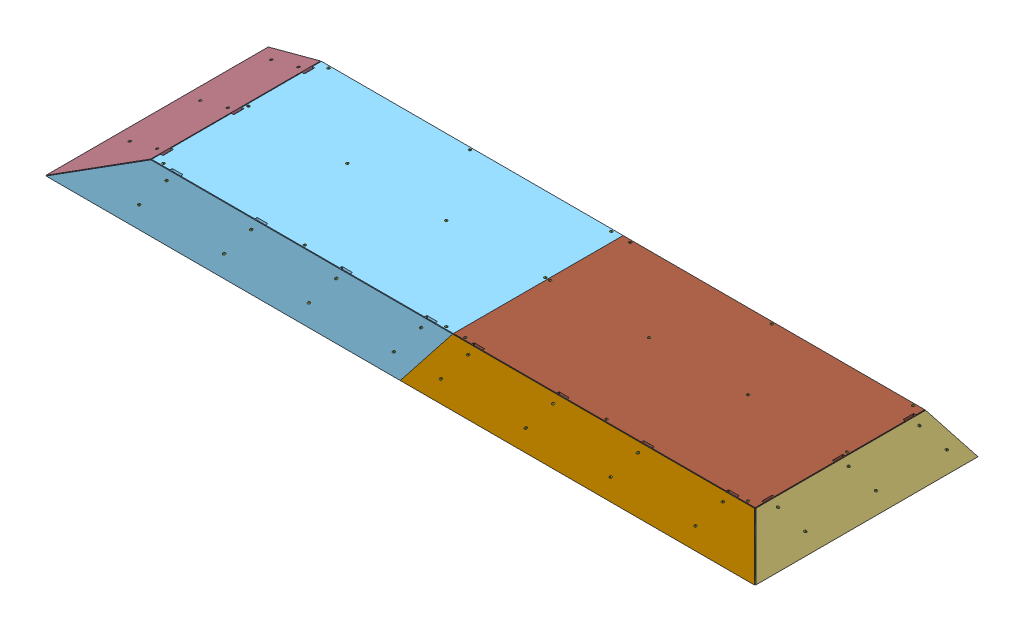
SolidWorks assembly GE-19062, configuration Default. Lengths in mm.
Overall size (3824.12 126.58 1202.44).
172 component instances, 14 part files, 19 mates.
Components (placement in the parent):
- GE-19067-1: GE-19067 [GE-19067-red] at (605.9548 862.858 1212.4726) size (1625.6 77.99 917.59)
  - GE-19063-1: GE-19063 [Default] at origin size (1625.6 63.5 917.59)
    - GE-19066-2: GE-19066 [Default] at (812.8 0 -457.2) x (0 0 -1) z (1 0 0) size (25.4 63.5 1625.6)
    - GE-19064-2: GE-19064 [Default] at (-812.8 0 -430.5376) x (-1 0 0) z (0 0 -1) size (25.4 63.5 910.59)
    - GE-19064-3: GE-19064 [Default] at (812.8 0 430.5224) size (25.4 63.5 910.59)
    - GE-19066-3: GE-19066 [Default] at (-812.8 0 457.1848) x (0 0 1) z (-1 0 0) size (25.4 63.5 1625.6)
    - GE-19065-1: GE-19065 [Default] at (279.4 0 -0.0076) size (25.4 63.5 910.59)
    - GE-19065-2: GE-19065 [Default] at (-279.4 63.5 -0.0076) x (-1 0 0) z (0 0 1) size (25.4 63.5 910.59)
    - rivet_.1875_.126-.25-2: rivet_.1875_.126-.25 [Default] at (-800.1 50.8 457.1848) size (10.01 10.01 13.03)
    - rivet_.1875_.126-.25-10: rivet_.1875_.126-.25 [Default] at (-266.7 50.8 457.1848) x (0.959125 0.282984 0) z (0 0 1) size (10.01 10.01 13.03)
    - rivet_.1875_.126-.25-11: rivet_.1875_.126-.25 [Default] at (-266.7 12.7 457.1848) x (0.928571 0.371154 0) z (0 0 1) size (10.01 10.01 13.03)
    - rivet_.1875_.126-.25-12: rivet_.1875_.126-.25 [Default] at (266.7 50.8 457.1848) x (0.906989 0.421154 0) z (0 0 1) size (10.01 10.01 13.03)
    - rivet_.1875_.126-.25-13: rivet_.1875_.126-.25 [Default] at (266.7 12.7 457.1848) x (0.902849 0.429957 0) z (0 0 1) size (10.01 10.01 13.03)
    - rivet_.1875_.126-.25-14: rivet_.1875_.126-.25 [Default] at (800.1 50.8 457.1848) x (0.919615 0.39282 0) z (0 0 1) size (10.01 10.01 13.03)
    - rivet_.1875_.126-.25-15: rivet_.1875_.126-.25 [Default] at (800.1 12.7 457.1848) x (0.952324 0.305088 0) z (0 0 1) size (10.01 10.01 13.03)
    - rivet_.1875_.126-.25-18: rivet_.1875_.126-.25 [Default] at (-800.1 12.7 457.1848) x (0.987351 0.158553 0) z (0 0 1) size (10.01 10.01 13.03)
    - rivet_.1875_.126-.25-20: rivet_.1875_.126-.25 [Default] at (800.1 50.8 -457.2) x (1 0 0) z (0 0 -1) size (10.01 10.01 13.03)
    - rivet_.1875_.126-.25-21: rivet_.1875_.126-.25 [Default] at (800.1 12.7 -457.2) x (0.987351 0.158553 0) z (0 0 -1) size (10.01 10.01 13.03)
    - rivet_.1875_.126-.25-22: rivet_.1875_.126-.25 [Default] at (266.7 50.8 -457.2) x (0.959125 0.282984 0) z (0 0 -1) size (10.01 10.01 13.03)
    - rivet_.1875_.126-.25-23: rivet_.1875_.126-.25 [Default] at (266.7 12.7 -457.2) x (0.928571 0.371154 0) z (0 0 -1) size (10.01 10.01 13.03)
    - rivet_.1875_.126-.25-24: rivet_.1875_.126-.25 [Default] at (-266.7 50.8 -457.2) x (0.906989 0.421154 0) z (0 0 -1) size (10.01 10.01 13.03)
    - rivet_.1875_.126-.25-25: rivet_.1875_.126-.25 [Default] at (-266.7 12.7 -457.2) x (0.902849 0.429957 0) z (0 0 -1) size (10.01 10.01 13.03)
    - rivet_.1875_.126-.25-26: rivet_.1875_.126-.25 [Default] at (-800.1 50.8 -457.2) x (0.919615 0.39282 0) z (0 0 -1) size (10.01 10.01 13.03)
    - rivet_.1875_.126-.25-27: rivet_.1875_.126-.25 [Default] at (-800.1 12.7 -457.2) x (0.952324 0.305088 0) z (0 0 -1) size (10.01 10.01 13.03)
  - GE-19068-1: GE-19068 [GE-19068-red] at (812.8 76.2 457.1848) x (-1 0 0) z (0 0 1) size (1625.6 12.7 914.4)
  - nylock_.25_20-1: nylock_.25_20 [Default] at (-762 61.6026 444.4848) x (-1 0 0) z (0 0 1) size (11.11 7.94 12.83)
  - nylock_.25_20-2: nylock_.25_20 [Default] at (0 61.6026 444.4848) x (-0.982082 0 0.188455) z (0.188455 0 0.982082) size (11.11 7.94 12.83)
  - nylock_.25_20-3: nylock_.25_20 [Default] at (762 61.6026 444.4848) x (-0.918365 0 0.395734) z (0.395734 0 0.918365) size (11.11 7.94 12.83)
  - nylock_.25_20-4: nylock_.25_20 [Default] at (800.1 61.6026 -50.8076) x (-0.8 0 0.6) z (0.6 0 0.8) size (11.11 7.94 12.83)
  - nylock_.25_20-5: nylock_.25_20 [Default] at (266.7 61.6026 -50.8076) x (-0.63358 0 0.773678) z (0.773678 0 0.63358) size (11.11 7.94 12.83)
  - nylock_.25_20-8: nylock_.25_20 [Default] at (-800.1 61.6026 -50.8076) x (0.999877 0 -0.015704) z (-0.015704 0 -0.999877) size (11.11 7.94 12.83)
  - nylock_.25_20-9: nylock_.25_20 [Default] at (-762 61.6026 -444.5) x (-0.263225 0 0.964735) z (0.964735 0 0.263225) size (11.11 7.94 12.83)
  - nylock_.25_20-10: nylock_.25_20 [Default] at (0 61.6026 -444.5) x (-0.120178 0 0.992752) z (0.992752 0 0.120178) size (11.11 7.94 12.83)
  - nylock_.25_20-11: nylock_.25_20 [Default] at (762 61.6026 -444.5) x (-0.030377 0 0.999538) z (0.999538 0 0.030377) size (11.11 7.94 12.83)
  - nylock_.25_20-12: nylock_.25_20 [Default] at (-266.7 61.6026 -50.8076) x (0.546944 0 0.837169) z (0.837169 0 -0.546944) size (11.11 7.94 12.83)
  - flat_hex_.25_20_1-1: flat_hex_.25_20_1 [91253A542] at (762 76.2 -444.5152) x (1 0 0) z (0 1 0) size (13.49 13.49 25.61)
  - flat_hex_.25_20_1-12: flat_hex_.25_20_1 [91253A542] at (0 76.2 -444.5152) x (0.982082 0 -0.188455) z (0 1 0) size (13.49 13.49 25.61)
  - flat_hex_.25_20_1-13: flat_hex_.25_20_1 [91253A542] at (-762 76.2 -444.5152) x (0.918365 0 -0.395734) z (0 1 0) size (13.49 13.49 25.61)
  - flat_hex_.25_20_1-14: flat_hex_.25_20_1 [91253A542] at (-800.1 76.2 -50.8152) x (0.8 0 -0.6) z (0 1 0) size (13.49 13.49 25.61)
  - flat_hex_.25_20_1-15: flat_hex_.25_20_1 [91253A542] at (-762 76.2 444.4848) x (0.63358 0 -0.773678) z (0 1 0) size (13.49 13.49 25.61)
  - flat_hex_.25_20_1-16: flat_hex_.25_20_1 [91253A542] at (0 76.2 444.4848) x (0.443629 0 -0.896211) z (0 1 0) size (13.49 13.49 25.61)
  - flat_hex_.25_20_1-17: flat_hex_.25_20_1 [91253A542] at (-266.7 76.2 -50.8152) x (0.263225 0 -0.964735) z (0 1 0) size (13.49 13.49 25.61)
  - flat_hex_.25_20_1-18: flat_hex_.25_20_1 [91253A542] at (266.7 76.2 -50.8152) x (0.120178 0 -0.992752) z (0 1 0) size (13.49 13.49 25.61)
  - flat_hex_.25_20_1-19: flat_hex_.25_20_1 [91253A542] at (762 76.2 444.4848) x (0.030377 0 -0.999538) z (0 1 0) size (13.49 13.49 25.61)
  - flat_hex_.25_20_1-20: flat_hex_.25_20_1 [91253A542] at (800.1 76.2 -50.8152) x (0 0 -1) z (0 1 0) size (13.49 13.49 25.61)
  - Hook_1_36-1: Hook_1_36 [Default] at (-787.4 -1.5875 457.2) x (0 0 -1) z (1 0 0) size (914.4 1.59 25.4)
  - Hook_1_36-2: Hook_1_36 [Default] at (812.8 -1.5875 457.2) x (0 0 -1) z (1 0 0) size (914.4 1.59 25.4)
- GE-19053-1: GE-19053 [Default] at (2243.466 893.8913 1808.0826) x (1 0 0) z (0 -0.259056 0.965862) size (1908.66 51.01 298.45)
  - GE-19054-1: GE-19054 [Default] at (-11.9112 -4.3385 -141.1312) size (1908.66 12.7 292.1)
  - GE-19055-1: GE-19055 [Default] at (-719.9362 -42.4385 -142.706) size (44.45 38.1 228.6)
  - GE-19055-2: GE-19055 [Default] at (-262.7362 -42.4385 -142.706) size (44.45 38.1 228.6)
  - GE-19055-3: GE-19055 [Default] at (194.4638 -42.4385 -142.706) size (44.45 38.1 228.6)
  - GE-19055-4: GE-19055 [Default] at (651.6638 -42.4385 -142.706) size (44.45 38.1 228.6)
  - nylock_.25_20-1: nylock_.25_20 [Default] at (673.8888 -9.1137 -96.6812) x (-1 0 0) z (0 0 1) size (11.11 7.94 12.83)
  - nylock_.25_20-2: nylock_.25_20 [Default] at (673.8888 -9.1137 55.7188) x (-0.982082 0 0.188455) z (0.188455 0 0.982082) size (11.11 7.94 12.83)
  - nylock_.25_20-3: nylock_.25_20 [Default] at (216.6888 -9.1137 -96.6812) x (-0.918365 0 0.395734) z (0.395734 0 0.918365) size (11.11 7.94 12.83)
  - nylock_.25_20-4: nylock_.25_20 [Default] at (216.6888 -9.1137 55.7188) x (-0.8 0 0.6) z (0.6 0 0.8) size (11.11 7.94 12.83)
  - nylock_.25_20-5: nylock_.25_20 [Default] at (-240.5112 -9.1137 -96.6812) x (-0.63358 0 0.773678) z (0.773678 0 0.63358) size (11.11 7.94 12.83)
  - nylock_.25_20-6: nylock_.25_20 [Default] at (-240.5112 -9.1137 55.7188) x (-0.443629 0 0.896211) z (0.896211 0 0.443629) size (11.11 7.94 12.83)
  - nylock_.25_20-7: nylock_.25_20 [Default] at (-697.7112 -9.1137 -96.6812) x (-0.263225 0 0.964735) z (0.964735 0 0.263225) size (11.11 7.94 12.83)
  - nylock_.25_20-8: nylock_.25_20 [Default] at (-697.7112 -9.1137 55.7188) x (-0.120178 0 0.992752) z (0.992752 0 0.120178) size (11.11 7.94 12.83)
  - flat_hex_.25_20_1-1: flat_hex_.25_20_1 [91253A542] at (673.8888 8.3615 -96.6812) x (1 0 0) z (0 1 0) size (13.49 13.49 25.61)
  - flat_hex_.25_20_1-2: flat_hex_.25_20_1 [91253A542] at (673.8888 8.3615 55.7188) x (0.982082 0 -0.188455) z (0 1 0) size (13.49 13.49 25.61)
  - flat_hex_.25_20_1-3: flat_hex_.25_20_1 [91253A542] at (216.6888 8.3615 -96.6812) x (0.918365 0 -0.395734) z (0 1 0) size (13.49 13.49 25.61)
  - flat_hex_.25_20_1-4: flat_hex_.25_20_1 [91253A542] at (216.6888 8.3615 55.7188) x (0.8 0 -0.6) z (0 1 0) size (13.49 13.49 25.61)
  - flat_hex_.25_20_1-5: flat_hex_.25_20_1 [91253A542] at (-240.5112 8.3615 55.7188) x (0.63358 0 -0.773678) z (0 1 0) size (13.49 13.49 25.61)
  - flat_hex_.25_20_1-6: flat_hex_.25_20_1 [91253A542] at (-240.5112 8.3615 -96.6812) x (0.443629 0 -0.896211) z (0 1 0) size (13.49 13.49 25.61)
  - flat_hex_.25_20_1-7: flat_hex_.25_20_1 [91253A542] at (-697.7112 8.3615 -96.6812) x (0.263225 0 -0.964735) z (0 1 0) size (13.49 13.49 25.61)
  - flat_hex_.25_20_1-8: flat_hex_.25_20_1 [91253A542] at (-697.7112 8.3615 55.7188) x (0.120178 0 -0.992752) z (0 1 0) size (13.49 13.49 25.61)
- GE-19051-2: GE-19051 [Default] at (2231.5548 862.858 1212.4726) size (1625.6 77.99 917.59)
  - GE-19063-1: GE-19063 [Default] at origin size (1625.6 63.5 917.59)
    - GE-19066-2: GE-19066 [Default] at (812.8 0 -457.2) x (0 0 -1) z (1 0 0) size (25.4 63.5 1625.6)
    - GE-19064-2: GE-19064 [Default] at (-812.8 0 -430.5376) x (-1 0 0) z (0 0 -1) size (25.4 63.5 910.59)
    - GE-19064-3: GE-19064 [Default] at (812.8 0 430.5224) size (25.4 63.5 910.59)
    - GE-19066-3: GE-19066 [Default] at (-812.8 0 457.1848) x (0 0 1) z (-1 0 0) size (25.4 63.5 1625.6)
    - GE-19065-1: GE-19065 [Default] at (279.4 0 -0.0076) size (25.4 63.5 910.59)
    - GE-19065-2: GE-19065 [Default] at (-279.4 63.5 -0.0076) x (-1 0 0) z (0 0 1) size (25.4 63.5 910.59)
    - rivet_.1875_.126-.25-2: rivet_.1875_.126-.25 [Default] at (-800.1 50.8 457.1848) size (10.01 10.01 13.03)
    - rivet_.1875_.126-.25-10: rivet_.1875_.126-.25 [Default] at (-266.7 50.8 457.1848) x (0.959125 0.282984 0) z (0 0 1) size (10.01 10.01 13.03)
    - rivet_.1875_.126-.25-11: rivet_.1875_.126-.25 [Default] at (-266.7 12.7 457.1848) x (0.928571 0.371154 0) z (0 0 1) size (10.01 10.01 13.03)
    - rivet_.1875_.126-.25-12: rivet_.1875_.126-.25 [Default] at (266.7 50.8 457.1848) x (0.906989 0.421154 0) z (0 0 1) size (10.01 10.01 13.03)
    - rivet_.1875_.126-.25-13: rivet_.1875_.126-.25 [Default] at (266.7 12.7 457.1848) x (0.902849 0.429957 0) z (0 0 1) size (10.01 10.01 13.03)
    - rivet_.1875_.126-.25-14: rivet_.1875_.126-.25 [Default] at (800.1 50.8 457.1848) x (0.919615 0.39282 0) z (0 0 1) size (10.01 10.01 13.03)
    - rivet_.1875_.126-.25-15: rivet_.1875_.126-.25 [Default] at (800.1 12.7 457.1848) x (0.952324 0.305088 0) z (0 0 1) size (10.01 10.01 13.03)
    - rivet_.1875_.126-.25-18: rivet_.1875_.126-.25 [Default] at (-800.1 12.7 457.1848) x (0.987351 0.158553 0) z (0 0 1) size (10.01 10.01 13.03)
    - rivet_.1875_.126-.25-20: rivet_.1875_.126-.25 [Default] at (800.1 50.8 -457.2) x (1 0 0) z (0 0 -1) size (10.01 10.01 13.03)
    - rivet_.1875_.126-.25-21: rivet_.1875_.126-.25 [Default] at (800.1 12.7 -457.2) x (0.987351 0.158553 0) z (0 0 -1) size (10.01 10.01 13.03)
    - rivet_.1875_.126-.25-22: rivet_.1875_.126-.25 [Default] at (266.7 50.8 -457.2) x (0.959125 0.282984 0) z (0 0 -1) size (10.01 10.01 13.03)
    - rivet_.1875_.126-.25-23: rivet_.1875_.126-.25 [Default] at (266.7 12.7 -457.2) x (0.928571 0.371154 0) z (0 0 -1) size (10.01 10.01 13.03)
    - rivet_.1875_.126-.25-24: rivet_.1875_.126-.25 [Default] at (-266.7 50.8 -457.2) x (0.906989 0.421154 0) z (0 0 -1) size (10.01 10.01 13.03)
    - rivet_.1875_.126-.25-25: rivet_.1875_.126-.25 [Default] at (-266.7 12.7 -457.2) x (0.902849 0.429957 0) z (0 0 -1) size (10.01 10.01 13.03)
    - rivet_.1875_.126-.25-26: rivet_.1875_.126-.25 [Default] at (-800.1 50.8 -457.2) x (0.919615 0.39282 0) z (0 0 -1) size (10.01 10.01 13.03)
    - rivet_.1875_.126-.25-27: rivet_.1875_.126-.25 [Default] at (-800.1 12.7 -457.2) x (0.952324 0.305088 0) z (0 0 -1) size (10.01 10.01 13.03)
  - GE-19052-1: GE-19052 [Default] at (-812.8 63.5 457.2) size (1625.6 12.7 914.4)
  - nylock_.25_20-1: nylock_.25_20 [Default] at (-762 61.6026 444.4848) x (-1 0 0) z (0 0 1) size (11.11 7.94 12.83)
  - nylock_.25_20-2: nylock_.25_20 [Default] at (0 61.6026 444.4848) x (-0.982082 0 0.188455) z (0.188455 0 0.982082) size (11.11 7.94 12.83)
  - nylock_.25_20-3: nylock_.25_20 [Default] at (762 61.6026 444.4848) x (-0.918365 0 0.395734) z (0.395734 0 0.918365) size (11.11 7.94 12.83)
  - nylock_.25_20-4: nylock_.25_20 [Default] at (800.1 61.6026 -50.8076) x (-0.8 0 0.6) z (0.6 0 0.8) size (11.11 7.94 12.83)
  - nylock_.25_20-5: nylock_.25_20 [Default] at (266.7 61.6026 -50.8076) x (-0.63358 0 0.773678) z (0.773678 0 0.63358) size (11.11 7.94 12.83)
  - nylock_.25_20-8: nylock_.25_20 [Default] at (-800.1 61.6026 -50.8076) x (0.999877 0 -0.015704) z (-0.015704 0 -0.999877) size (11.11 7.94 12.83)
  - nylock_.25_20-9: nylock_.25_20 [Default] at (-762 61.6026 -444.5) x (-0.263225 0 0.964735) z (0.964735 0 0.263225) size (11.11 7.94 12.83)
  - nylock_.25_20-10: nylock_.25_20 [Default] at (0 61.6026 -444.5) x (-0.120178 0 0.992752) z (0.992752 0 0.120178) size (11.11 7.94 12.83)
  - nylock_.25_20-11: nylock_.25_20 [Default] at (762 61.6026 -444.5) x (-0.030377 0 0.999538) z (0.999538 0 0.030377) size (11.11 7.94 12.83)
  - nylock_.25_20-12: nylock_.25_20 [Default] at (-266.7 61.6026 -50.8076) x (0.546944 0 0.837169) z (0.837169 0 -0.546944) size (11.11 7.94 12.83)
  - flat_hex_.25_20_1-1: flat_hex_.25_20_1 [91253A542] at (762 76.2 -444.5) x (1 0 0) z (0 1 0) size (13.49 13.49 25.61)
  - flat_hex_.25_20_1-2: flat_hex_.25_20_1 [91253A542] at (0 76.2 -444.5) x (0.982082 0 -0.188455) z (0 1 0) size (13.49 13.49 25.61)
  - flat_hex_.25_20_1-3: flat_hex_.25_20_1 [91253A542] at (-762 76.2 -444.5) x (0.918365 0 -0.395734) z (0 1 0) size (13.49 13.49 25.61)
  - flat_hex_.25_20_1-4: flat_hex_.25_20_1 [91253A542] at (-800.1 76.2 -50.8) x (0.8 0 -0.6) z (0 1 0) size (13.49 13.49 25.61)
  - flat_hex_.25_20_1-5: flat_hex_.25_20_1 [91253A542] at (-762 76.2 444.5) x (0.63358 0 -0.773678) z (0 1 0) size (13.49 13.49 25.61)
  - flat_hex_.25_20_1-6: flat_hex_.25_20_1 [91253A542] at (0 76.2 444.5) x (0.443629 0 -0.896211) z (0 1 0) size (13.49 13.49 25.61)
  - flat_hex_.25_20_1-7: flat_hex_.25_20_1 [91253A542] at (-266.7 76.2 -50.8) x (0.263225 0 -0.964735) z (0 1 0) size (13.49 13.49 25.61)
  - flat_hex_.25_20_1-8: flat_hex_.25_20_1 [91253A542] at (266.7 76.2 -50.8) x (0.120178 0 -0.992752) z (0 1 0) size (13.49 13.49 25.61)
  - flat_hex_.25_20_1-9: flat_hex_.25_20_1 [91253A542] at (762 76.2 444.5) x (0.030377 0 -0.999538) z (0 1 0) size (13.49 13.49 25.61)
  - flat_hex_.25_20_1-10: flat_hex_.25_20_1 [91253A542] at (800.1 76.2 -50.8) x (0 0 -1) z (0 1 0) size (13.49 13.49 25.61)
  - Hook_1_36-1: Hook_1_36 [Default] at (-787.4 -1.5875 457.2) x (0 0 -1) z (1 0 0) size (914.4 1.59 25.4)
  - Hook_1_36-2: Hook_1_36 [Default] at (787.4 -1.5875 -457.2) x (0 0 1) z (-1 0 0) size (914.4 1.59 25.4)
- GE-19057-1: GE-19057 [Default] at (3182.7801 893.8913 1200.5537) x (0 0 -1) z (0.965862 -0.259056 0) size (1197.46 51.01 298.45)
  - GE-19056-1: GE-19056 [Default] at (-11.9112 -4.3385 -141.1312) size (1197.46 12.7 292.1)
  - GE-19055-1: GE-19055 [Default] at (-415.1362 -42.4385 -142.706) size (44.45 38.1 228.6)
  - GE-19055-2: GE-19055 [Default] at (-34.1362 -42.4385 -142.706) size (44.45 38.1 228.6)
  - GE-19055-3: GE-19055 [Default] at (346.8638 -42.4385 -142.706) size (44.45 38.1 228.6)
  - nylock_.25_20-1: nylock_.25_20 [Default] at (369.0888 -9.1137 -96.6812) x (-0.837169 0 -0.546944) z (-0.546944 0 0.837169) size (11.11 7.94 12.83)
  - nylock_.25_20-2: nylock_.25_20 [Default] at (369.0888 -9.1137 55.7188) x (-0.925243 0 -0.379375) z (-0.379375 0 0.925243) size (11.11 7.94 12.83)
  - nylock_.25_20-3: nylock_.25_20 [Default] at (-11.9112 -9.1137 -96.6812) x (-0.985271 0 -0.170998) z (-0.170998 0 0.985271) size (11.11 7.94 12.83)
  - nylock_.25_20-4: nylock_.25_20 [Default] at (-11.9112 -9.1137 55.7188) x (-0.997902 0 0.064746) z (0.064746 0 0.997902) size (11.11 7.94 12.83)
  - nylock_.25_20-5: nylock_.25_20 [Default] at (-392.9112 -9.1137 -96.6812) x (-0.953572 0 0.301166) z (0.301166 0 0.953572) size (11.11 7.94 12.83)
  - nylock_.25_20-6: nylock_.25_20 [Default] at (-392.9112 -9.1137 55.7188) x (-0.86157 0 0.507639) z (0.507639 0 0.86157) size (11.11 7.94 12.83)
  - flat_hex_.25_20_1-1: flat_hex_.25_20_1 [91253A542] at (369.0888 8.3615 -96.6812) x (1 0 0) z (0 1 0) size (13.49 13.49 25.61)
  - flat_hex_.25_20_1-2: flat_hex_.25_20_1 [91253A542] at (369.0888 8.3615 55.7188) x (0.982082 0 -0.188455) z (0 1 0) size (13.49 13.49 25.61)
  - flat_hex_.25_20_1-3: flat_hex_.25_20_1 [91253A542] at (-11.9112 8.3615 -96.6812) x (0.918365 0 -0.395734) z (0 1 0) size (13.49 13.49 25.61)
  - flat_hex_.25_20_1-4: flat_hex_.25_20_1 [91253A542] at (-11.9112 8.3615 55.7188) x (0.8 0 -0.6) z (0 1 0) size (13.49 13.49 25.61)
  - flat_hex_.25_20_1-5: flat_hex_.25_20_1 [91253A542] at (-392.9112 8.3615 55.7188) x (0.63358 0 -0.773678) z (0 1 0) size (13.49 13.49 25.61)
  - flat_hex_.25_20_1-6: flat_hex_.25_20_1 [91253A542] at (-392.9112 8.3615 -96.6812) x (0.443629 0 -0.896211) z (0 1 0) size (13.49 13.49 25.61)
- GE-19058-1: GE-19058 [Default] at (-345.2705 893.8913 1224.3762) x (0 0 1) z (-0.965862 -0.259056 0) size (1197.46 51.01 298.45)
  - GE-19059-1: GE-19059 [Default] at (-11.9112 -4.3385 -141.1312) size (1197.46 12.7 292.1)
  - GE-19055-1: GE-19055 [Default] at (-415.1362 -42.4385 -142.706) size (44.45 38.1 228.6)
  - GE-19055-2: GE-19055 [Default] at (-34.1362 -42.4385 -142.706) size (44.45 38.1 228.6)
  - GE-19055-3: GE-19055 [Default] at (346.8638 -42.4385 -142.706) size (44.45 38.1 228.6)
  - nylock_.25_20-1: nylock_.25_20 [Default] at (369.0888 -9.1137 -96.6812) x (-0.837169 0 -0.546944) z (-0.546944 0 0.837169) size (11.11 7.94 12.83)
  - nylock_.25_20-2: nylock_.25_20 [Default] at (369.0888 -9.1137 55.7188) x (-0.925243 0 -0.379375) z (-0.379375 0 0.925243) size (11.11 7.94 12.83)
  - nylock_.25_20-4: nylock_.25_20 [Default] at (-11.9112 -9.1137 -96.6812) x (-0.997902 0 0.064746) z (0.064746 0 0.997902) size (11.11 7.94 12.83)
  - nylock_.25_20-5: nylock_.25_20 [Default] at (-11.9112 -9.1137 55.7188) x (-0.953572 0 0.301166) z (0.301166 0 0.953572) size (11.11 7.94 12.83)
  - nylock_.25_20-6: nylock_.25_20 [Default] at (-392.9112 -9.1137 -96.6812) x (-0.86157 0 0.507639) z (0.507639 0 0.86157) size (11.11 7.94 12.83)
  - nylock_.25_20-7: nylock_.25_20 [Default] at (-392.9112 -9.1137 55.7188) x (-0.748019 0 0.663677) z (0.663677 0 0.748019) size (11.11 7.94 12.83)
  - flat_hex_.25_20_1-1: flat_hex_.25_20_1 [91253A542] at (369.0888 8.3615 -96.6812) x (1 0 0) z (0 1 0) size (13.49 13.49 25.61)
  - flat_hex_.25_20_1-2: flat_hex_.25_20_1 [91253A542] at (369.0888 8.3615 55.7188) x (0.982082 0 -0.188455) z (0 1 0) size (13.49 13.49 25.61)
  - flat_hex_.25_20_1-3: flat_hex_.25_20_1 [91253A542] at (-11.9112 8.3615 55.7188) x (0.918365 0 -0.395734) z (0 1 0) size (13.49 13.49 25.61)
  - flat_hex_.25_20_1-4: flat_hex_.25_20_1 [91253A542] at (-11.9112 8.3615 -96.6812) x (0.8 0 -0.6) z (0 1 0) size (13.49 13.49 25.61)
  - flat_hex_.25_20_1-5: flat_hex_.25_20_1 [91253A542] at (-392.9112 8.3615 -96.6812) x (0.63358 0 -0.773678) z (0 1 0) size (13.49 13.49 25.61)
  - flat_hex_.25_20_1-6: flat_hex_.25_20_1 [91253A542] at (-392.9112 8.3615 55.7188) x (0.443629 0 -0.896211) z (0 1 0) size (13.49 13.49 25.61)
- GE-19060-1: GE-19060 [Default] at (617.866 893.8913 1808.0826) x (1 0 0) z (0 -0.259056 0.965862) size (1908.66 51.01 298.45)
  - GE-19061-1: GE-19061 [Default] at (-11.9112 -4.3385 -141.1312) size (1908.66 12.7 292.1)
  - GE-19055-1: GE-19055 [Default] at (-719.9362 -42.4385 -142.706) size (44.45 38.1 228.6)
  - GE-19055-2: GE-19055 [Default] at (-262.7362 -42.4385 -142.706) size (44.45 38.1 228.6)
  - GE-19055-3: GE-19055 [Default] at (194.4638 -42.4385 -142.706) size (44.45 38.1 228.6)
  - GE-19055-4: GE-19055 [Default] at (651.6638 -42.4385 -142.706) size (44.45 38.1 228.6)
  - nylock_.25_20-1: nylock_.25_20 [Default] at (673.8888 -9.1137 -96.6812) x (-0.837169 0 -0.546944) z (-0.546944 0 0.837169) size (11.11 7.94 12.83)
  - nylock_.25_20-2: nylock_.25_20 [Default] at (673.8888 -9.1137 55.7188) x (-0.925243 0 -0.379375) z (-0.379375 0 0.925243) size (11.11 7.94 12.83)
  - nylock_.25_20-3: nylock_.25_20 [Default] at (216.6888 -9.1137 55.7188) x (-0.985271 0 -0.170998) z (-0.170998 0 0.985271) size (11.11 7.94 12.83)
  - nylock_.25_20-4: nylock_.25_20 [Default] at (216.6888 -9.1137 -96.6812) x (-0.997902 0 0.064746) z (0.064746 0 0.997902) size (11.11 7.94 12.83)
  - nylock_.25_20-5: nylock_.25_20 [Default] at (-240.5112 -9.1137 -96.6812) x (-0.953572 0 0.301166) z (0.301166 0 0.953572) size (11.11 7.94 12.83)
  - nylock_.25_20-6: nylock_.25_20 [Default] at (-240.5112 -9.1137 55.7188) x (-0.86157 0 0.507639) z (0.507639 0 0.86157) size (11.11 7.94 12.83)
  - nylock_.25_20-7: nylock_.25_20 [Default] at (-697.7112 -9.1137 55.7188) x (-0.748019 0 0.663677) z (0.663677 0 0.748019) size (11.11 7.94 12.83)
  - nylock_.25_20-8: nylock_.25_20 [Default] at (-697.7112 -9.1137 -96.6812) x (-0.643589 0 0.765371) z (0.765371 0 0.643589) size (11.11 7.94 12.83)
  - flat_hex_.25_20_1-1: flat_hex_.25_20_1 [91253A542] at (673.8888 8.3615 -96.6812) x (1 0 0) z (0 1 0) size (13.49 13.49 25.61)
  - flat_hex_.25_20_1-2: flat_hex_.25_20_1 [91253A542] at (673.8888 8.3615 55.7188) x (0.982082 0 -0.188455) z (0 1 0) size (13.49 13.49 25.61)
  - flat_hex_.25_20_1-3: flat_hex_.25_20_1 [91253A542] at (216.6888 8.3615 55.7188) x (0.918365 0 -0.395734) z (0 1 0) size (13.49 13.49 25.61)
  - flat_hex_.25_20_1-4: flat_hex_.25_20_1 [91253A542] at (216.6888 8.3615 -96.6812) x (0.8 0 -0.6) z (0 1 0) size (13.49 13.49 25.61)
  - flat_hex_.25_20_1-5: flat_hex_.25_20_1 [91253A542] at (-240.5112 8.3615 -96.6812) x (0.63358 0 -0.773678) z (0 1 0) size (13.49 13.49 25.61)
  - flat_hex_.25_20_1-6: flat_hex_.25_20_1 [91253A542] at (-240.5112 8.3615 55.7188) x (0.443629 0 -0.896211) z (0 1 0) size (13.49 13.49 25.61)
  - flat_hex_.25_20_1-7: flat_hex_.25_20_1 [91253A542] at (-697.7112 8.3615 55.7188) x (0.263225 0 -0.964735) z (0 1 0) size (13.49 13.49 25.61)
  - flat_hex_.25_20_1-8: flat_hex_.25_20_1 [91253A542] at (-697.7112 8.3615 -96.6812) x (0.120178 0 -0.992752) z (0 1 0) size (13.49 13.49 25.61)
Mates (geometry in assembly coordinates):
- Coincident1: coincident: plane of GE-19067-1/GE-19063-1/GE-19064-3 through (1418.7548 862.858 1642.995) normal (1 0 0); plane of GE-19051-2/GE-19063-1/GE-19064-2 through (1418.7548 862.858 781.935) normal (-1 0 0)
- Coincident2: coincident: plane of GE-19067-1/GE-19063-1/GE-19064-3 through (1418.7548 862.858 1642.995) normal (0 -1 0); plane of GE-19051-2/GE-19063-1/GE-19064-2 through (1418.7548 862.858 781.935) normal (0 -1 0)
- Coincident3: coincident: plane of GE-19067-1/GE-19063-1/GE-19066-3 through (-206.8452 862.858 1669.6573) normal (0 0 1); plane of GE-19051-2/GE-19063-1/GE-19066-3 through (1418.7548 862.858 1669.6573) normal (0 0 1)
- Distance1: distance = 3.175 mm: plane of GE-19057-1/GE-19055-1 through (3033.9518 889.8704 1571.24) normal (0 0 -1); plane of GE-19051-2/GE-19063-1/GE-19064-3 through (3044.3548 921.5828 1568.065) normal (0 0 1)
- Coincident5: coincident: line of GE-19051-2/GE-19063-1/GE-19064-3 through (3044.3548 921.5828 1618.865) axis (0 0 -1); plane of GE-19057-1/GE-19055-1 through (3042.5848 922.0576 1571.24) normal (-0.259056 -0.965862 0)
- Coincident6: coincident: plane of GE-19051-2/GE-19063-1/GE-19064-3 through (3044.3548 862.858 1642.995) normal (0 -1 0); line of GE-19057-1/GE-19056-1 through (3330.7612 862.858 1952.7296) axis (0 0 -1)
- Coincident7: coincident: line of GE-19051-2/GE-19063-1/GE-19064-3 through (3042.4574 921.5828 1618.865) axis (0 0 -1); plane of GE-19057-1/GE-19055-1 through (3033.9518 889.8704 1571.24) normal (0.965862 -0.259056 0)
- Distance2: distance = 3.175 mm: plane of GE-19053-1/GE-19055-1 through (1567.9798 889.8704 1659.2543) normal (1 0 0); plane of GE-19051-2/GE-19063-1/GE-19066-3 through (1571.1548 921.5828 1669.6573) normal (-1 0 0)
- Coincident9: coincident: plane of GE-19053-1/GE-19055-1 through (1567.9798 922.0576 1667.8873) normal (0 -0.965862 -0.259056); line of GE-19051-2/GE-19063-1/GE-19066-3 through (1520.3548 921.5828 1669.6573) axis (1 0 0)
- Coincident10: coincident: line of GE-19053-1/GE-19054-1 through (1418.7548 862.858 1956.0638) axis (1 0 0); plane of GE-19051-2/GE-19063-1/GE-19066-3 through (1418.7548 862.858 1669.6573) normal (0 -1 0)
- Coincident11: coincident: plane of GE-19053-1/GE-19055-1 through (1567.9798 889.8704 1659.2543) normal (0 -0.259056 0.965862); line of GE-19051-2/GE-19063-1/GE-19066-3 through (1520.3548 921.5828 1667.76) axis (1 0 0)
- Distance3: distance = 3.175 mm: plane of GE-19060-1/GE-19055-4 through (1313.9798 889.8704 1659.2543) normal (1 0 0); plane of GE-19067-1/GE-19063-1/GE-19066-3 through (1317.1548 921.5828 1669.6573) normal (-1 0 0)
- Coincident13: coincident: line of GE-19067-1/GE-19063-1/GE-19066-3 through (1266.3548 921.5828 1669.6573) axis (1 0 0); plane of GE-19060-1/GE-19055-4 through (1313.9798 922.0576 1667.8873) normal (0 -0.965862 -0.259056)
- Coincident14: coincident: plane of GE-19067-1/GE-19063-1/GE-19066-3 through (-206.8452 862.858 1669.6573) normal (0 -1 0); line of GE-19060-1/GE-19061-1 through (-489.9098 862.858 1956.0638) axis (1 0 0)
- Coincident15: coincident: line of GE-19067-1/GE-19063-1/GE-19066-3 through (1266.3548 921.5828 1667.76) axis (1 0 0); plane of GE-19060-1/GE-19055-4 through (1313.9798 889.8704 1659.2543) normal (0 -0.259056 0.965862)
- Distance4: distance = 3.175 mm: plane of GE-19058-1/GE-19055-1 through (-196.4422 889.8704 809.24) normal (0 0 -1); plane of GE-19067-1/GE-19063-1/GE-19064-2 through (-206.8452 921.5828 806.065) normal (0 0 1)
- Coincident17: coincident: line of GE-19067-1/GE-19063-1/GE-19064-2 through (-206.8452 921.5828 806.065) axis (0 0 1); plane of GE-19058-1/GE-19055-1 through (-205.0752 922.0576 853.69) normal (0.259056 -0.965862 0)
- Coincident18: coincident: plane of GE-19067-1/GE-19063-1/GE-19064-2 through (-206.8452 862.858 781.935) normal (0 -1 0); line of GE-19058-1/GE-19059-1 through (-493.2516 862.858 755.265) axis (0 0 1)
- Coincident19: coincident: line of GE-19067-1/GE-19063-1/GE-19064-2 through (-204.9478 921.5828 806.065) axis (0 0 1); plane of GE-19058-1/GE-19055-1 through (-196.4422 889.8704 853.69) normal (-0.965862 -0.259056 0)
